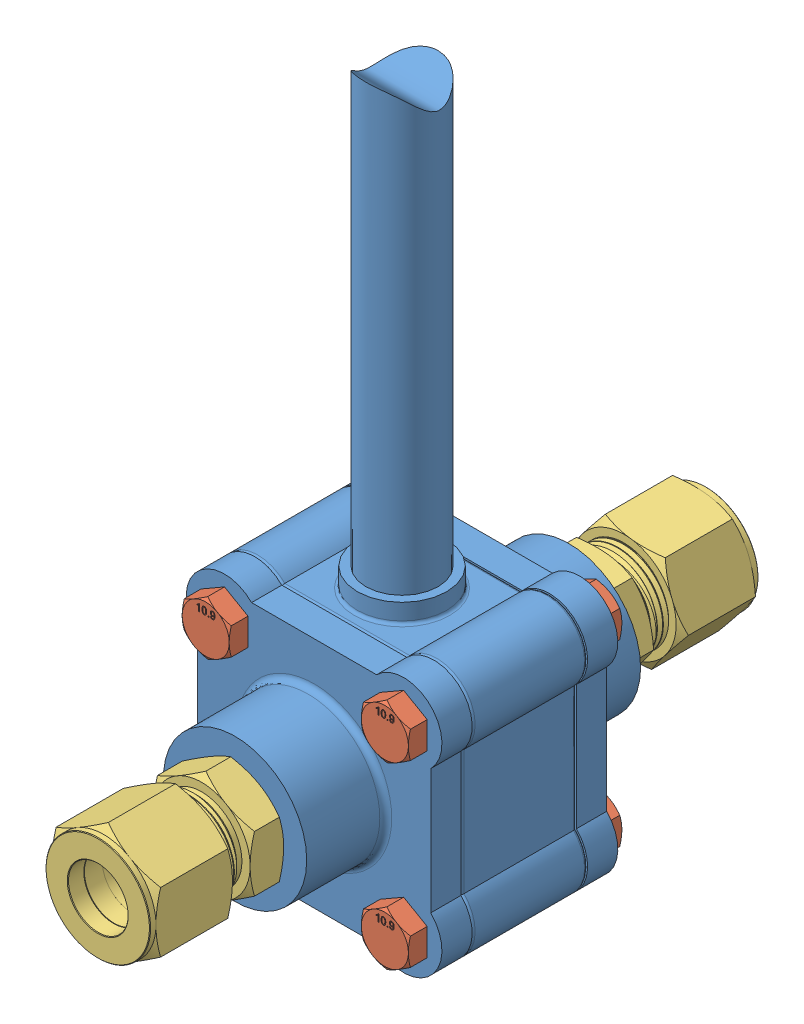
SolidWorks assembly Ball valve Assembly, configuration Default. Lengths in mm.
Overall size (54.4 149.67 129.42).
11 component instances, 3 part files, 2 mates.
Components (placement in the parent):
- Ball Valve-1: Ball Valve [Default] at (47.9446 27.2302 121.2666) size (54.4 149.67 71)
- 90854A132_HIGH-STRG ZINC YELLOW-CHROMATE PLTD CAP SCREW-1: 90854A132_HIGH-STRG ZINC YELLOW-CHROMATE PLTD CAP SCREW [90854A132] at (66.9946 46.2802 133.9666) x (0 0 -1) z (1 0 0) size (20.37 11.55 10)
- 90854A132_HIGH-STRG ZINC YELLOW-CHROMATE PLTD CAP SCREW-2: 90854A132_HIGH-STRG ZINC YELLOW-CHROMATE PLTD CAP SCREW [90854A132] at (66.9946 8.1802 133.9666) x (0 0 -1) z (1 0 0) size (20.37 11.55 10)
- 90854A132_HIGH-STRG ZINC YELLOW-CHROMATE PLTD CAP SCREW-3: 90854A132_HIGH-STRG ZINC YELLOW-CHROMATE PLTD CAP SCREW [90854A132] at (28.8946 46.2802 133.9666) x (0 0 -1) z (1 0 0) size (20.37 11.55 10)
- 90854A132_HIGH-STRG ZINC YELLOW-CHROMATE PLTD CAP SCREW-4: 90854A132_HIGH-STRG ZINC YELLOW-CHROMATE PLTD CAP SCREW [90854A132] at (28.8946 8.1802 133.9666) x (0 0 -1) z (1 0 0) size (20.37 11.55 10)
- 90854A132_HIGH-STRG ZINC YELLOW-CHROMATE PLTD CAP SCREW-5: 90854A132_HIGH-STRG ZINC YELLOW-CHROMATE PLTD CAP SCREW [90854A132] at (28.8946 46.2802 108.5666) x (0 0 1) z (-1 0 0) size (20.37 11.55 10)
- 90854A132_HIGH-STRG ZINC YELLOW-CHROMATE PLTD CAP SCREW-6: 90854A132_HIGH-STRG ZINC YELLOW-CHROMATE PLTD CAP SCREW [90854A132] at (66.9946 46.2802 108.5666) x (0 0 1) z (-1 0 0) size (20.37 11.55 10)
- 90854A132_HIGH-STRG ZINC YELLOW-CHROMATE PLTD CAP SCREW-7: 90854A132_HIGH-STRG ZINC YELLOW-CHROMATE PLTD CAP SCREW [90854A132] at (66.9946 8.1802 108.5666) x (0 0 1) z (-1 0 0) size (20.37 11.55 10)
- 90854A132_HIGH-STRG ZINC YELLOW-CHROMATE PLTD CAP SCREW-8: 90854A132_HIGH-STRG ZINC YELLOW-CHROMATE PLTD CAP SCREW [90854A132] at (28.8946 8.1802 108.5666) x (0 0 1) z (-1 0 0) size (20.37 11.55 10)
- 5182K133_TYPE 316 STAINLESS STEEL YOR-LOK TUBE FITTING-1: 5182K133_TYPE 316 STAINLESS STEEL YOR-LOK TUBE FITTING [5182K133] at (47.9446 27.2302 185.9766) size (22.23 25.66 43.85)
- 5182K133_TYPE 316 STAINLESS STEEL YOR-LOK TUBE FITTING-2: 5182K133_TYPE 316 STAINLESS STEEL YOR-LOK TUBE FITTING [5182K133] at (47.9446 27.2302 56.5566) x (-0.923728 -0.383049 0) z (0 0 -1) size (22.23 25.66 43.85)
Mates (geometry in assembly coordinates):
- Coincident1: coincident: plane of Ball Valve-1 through (47.9446 27.2302 139.9666) normal (0 0 1); plane of 90854A132_HIGH-STRG ZINC YELLOW-CHROMATE PLTD CAP SCREW-1 through (61.9946 43.3935 139.9666) normal (0 0 -1)
- Concentric1: concentric: circle of Ball Valve-1; circle of 90854A132_HIGH-STRG ZINC YELLOW-CHROMATE PLTD CAP SCREW-1
